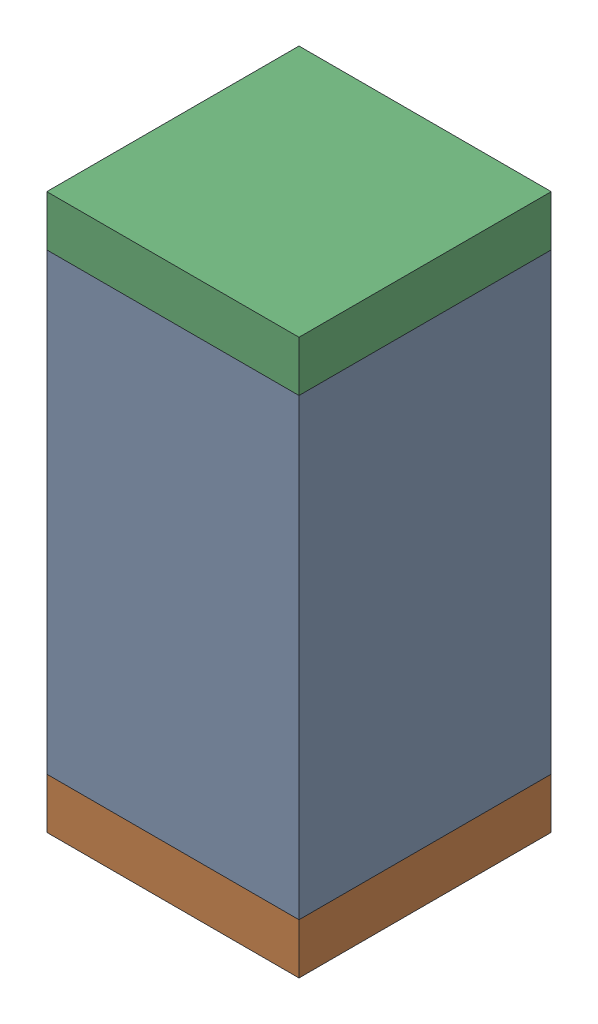
SolidWorks assembly C49, configuration Default. Lengths in mm.
Overall size (0.5 1.1 0.5).
6 component instances, 2 part files, 0 mates.
Components (placement in the parent):
- 791586336-1: 791586336 [Default] at (134.6 41.3 0) size (0.5 0.9 0.5)
  - Extruded_8-1: Extruded_8 [Default] at origin size (0.5 0.9 0.5)
- 810157360-1: 810157360 [Default] at (134.6 40.8 0) size (0.5 0.1 0.5)
  - Extruded_9-1: Extruded_9 [Default] at origin size (0.5 0.1 0.5)
- 810157360-2: 810157360 [Default] at (134.6 41.8 0) size (0.5 0.1 0.5)
  - Extruded_9-1: Extruded_9 [Default] at origin size (0.5 0.1 0.5)
